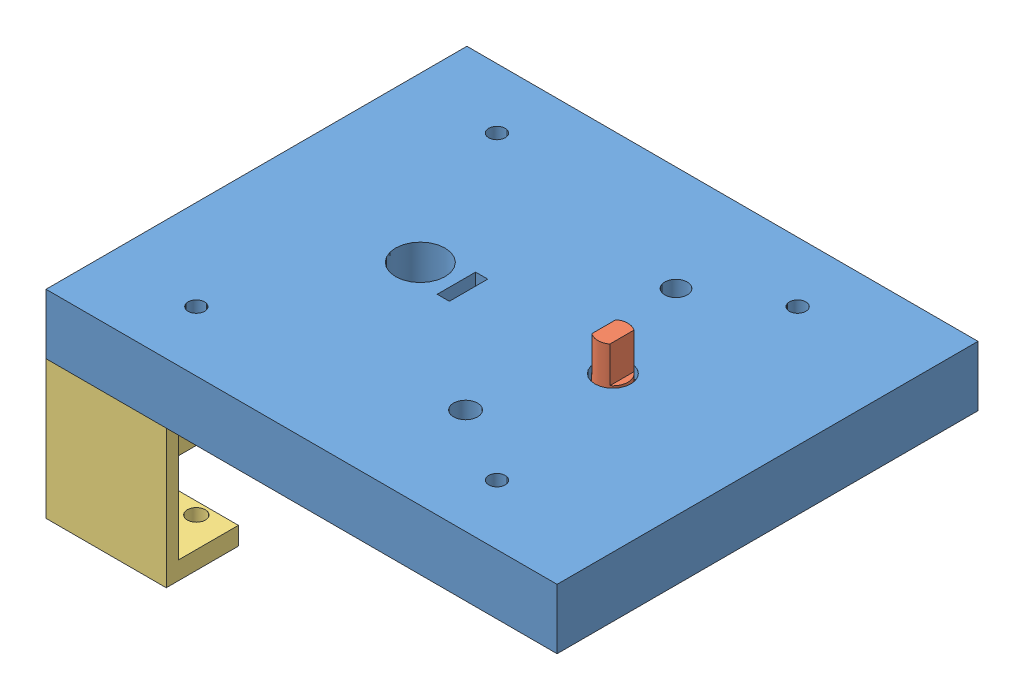
SolidWorks assembly Assem2, configuration Default. Lengths in mm.
Overall size (89.84 41 70).
3 component instances, 3 part files, 7 mates.
Components (placement in the parent):
- Base-1: Base [Default] at origin size (85 10 70)
- Stepper motor  1PC-1: Stepper motor  1PC [Default] at (0 6 0) x (0 0 1) z (0 1 0) size (42 71.12 29)
- Part2^Assem2-1: Part2^Assem2 [Default] x (-1 0 0) z (0 -1 0) size (85 70 23) (virtual)
Mates (geometry in assembly coordinates):
- Coincident1: coincident anti-aligned: plane of Base-1 through (0 6 0) normal (0 -1 0); plane of Stepper motor  1PC-1 through (0 6 0) normal (0 1 0)
- Concentric1: concentric aligned: cylinder of Base-1 through (0 6 0) axis (0 -1 0) radius 14.2; cylinder of Stepper motor  1PC-1 through (0 6 0) axis (0 -1 0) radius 14
- Concentric2: concentric aligned: cylinder of Base-1 through (0 10 -17.5) axis (0 -1 0) radius 1.875; cylinder of Stepper motor  1PC-1 through (0 19 -17.5) axis (0 -1 0) radius 2
- InPlace1: in place: plane of Base-1 through (0 0 0) normal (0 -1 0); plane of Part2^Assem2-1 through (0 0 0) normal (0 -1 0); moOrthogonalPlaneRef_w of Base-1 through (0 0 0) normal (0 -1 0); plane of Part2^Assem2-1 through (0 0 0) normal (0 0 -1); plane of Base-1 through (0 0 0) normal (0 -1 0); plane of Part2^Assem2-1 through (0 0 0) normal (-1 0 0); plane of Base-1 through (0 0 0) normal (0 -1 0); unknown of Part2^Assem2-1
- Coincident2: coincident aligned: plane of Base-1; plane of Part2^Assem2-1
- Coincident3: coincident aligned: moOrthogonalPlaneRef_w of Base-1 through (0 0 0) normal (0 0 -1); plane of Part2^Assem2-1 through (0 0 0) normal (0 0 -1)
- Coincident4: coincident anti-aligned: moOrthogonalPlaneRef_w of Base-1 through (0 0 0) normal (1 0 0); plane of Part2^Assem2-1 through (0 0 0) normal (-1 0 0)
